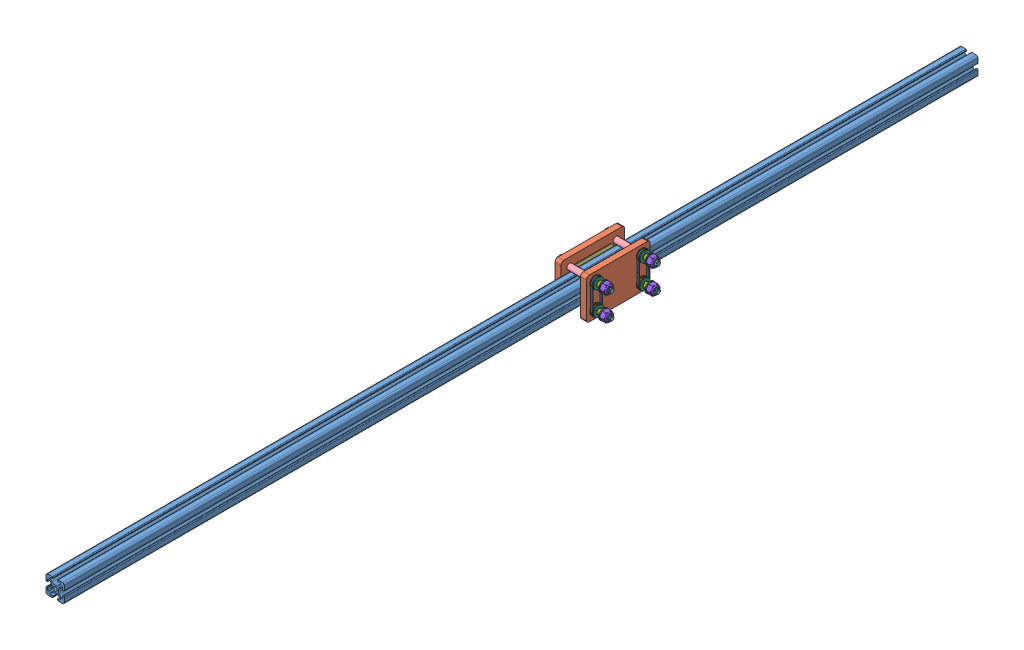
SolidWorks assembly Carriage, configuration Default. Lengths in mm.
Overall size (60.33 44.45 1000.12).
45 component instances, 10 part files, 37 mates.
Components (placement in the parent):
- 5537T237_T-Slotted Framing-1: 5537T237_T-Slotted Framing [5537T237] at origin size (19.99 19.99 1000.12)
- CarriagePlateHorizontal-1: CarriagePlateHorizontal [Default] at (17.1374 0 -99.2196) x (0 -1 0) z (-1 0 0) size (44.45 69.85 6.35)
- CarriagePlateHorizontal-2: CarriagePlateHorizontal [Default] at (-10.7874 0 -99.2196) x (0 -1 0) z (-1 0 0) size (44.45 69.85 6.35)
- Delrin Slide-1: Delrin Slide [Default] at (10.3937 0 -99.2196) x (-1 0 0) z (0 0 1) size (0.79 25.4 57.15)
- Delrin Slide-2: Delrin Slide [Default] at (-10.3937 0 -99.2196) x (-1 0 0) z (0 0 1) size (0.79 25.4 57.15)
- 8579K12 - Delrin Rod-1: 8579K12 - Delrin Rod [Default] at (0 13.175 -124.6196) x (0 -0.841097 0.540884) z (1 0 0) size (6.35 6.35 21.5)
- 91255A815_Button Head Hex Drive Screw-1: 91255A815_Button Head Hex Drive Screw [91255A815] at (-23.843 13.175 -124.6196) x (0 -0.96435 -0.26463) z (-1 0 0) size (9.17 9.17 60.33)
- 96765A125_Black-Oxide 18-8 Stainless Steel Washer-1: 96765A125_Black-Oxide 18-8 Stainless Steel Washer [96765A125] at (-21.2776 13.175 -124.6196) x (0 -0.999948 0.010183) z (0 0.010183 0.999948) size (11.11 0.97 11.11)
- 1986K71_302 Stainless Steel Corrosion-Resistant Compression Springs-1: 1986K71_302 Stainless Steel Corrosion-Resistant Compression Springs [Compressed] at (21.2776 13.175 -124.6196) x (0 -0.96435 -0.26463) z (-1 0 0) size (6.35 6.35 5.59)
- 96765A125_Black-Oxide 18-8 Stainless Steel Washer-2: 96765A125_Black-Oxide 18-8 Stainless Steel Washer [96765A125] at (20.3124 13.175 -124.6196) x (0 -0.999948 0.010183) z (0 0.010183 0.999948) size (11.11 0.97 11.11)
- 96765A125_Black-Oxide 18-8 Stainless Steel Washer-3: 96765A125_Black-Oxide 18-8 Stainless Steel Washer [96765A125] at (26.3576 13.175 -124.6196) x (0 -0.999948 0.010183) z (0 0.010183 0.999948) size (11.11 0.97 11.11)
- 94407A113_18-8 Stainless Steel Nylon-Insert Locknut-1: 94407A113_18-8 Stainless Steel Nylon-Insert Locknut [94407A113] at (27.3228 13.175 -124.6196) x (0 -0.999948 0.010183) z (0 0.010183 0.999948) size (9.53 6.11 11)
- 91255A815_Button Head Hex Drive Screw-2: 91255A815_Button Head Hex Drive Screw [91255A815] at (-23.843 -13.175 -73.8196) x (0 -0.96435 -0.26463) z (-1 0 0) size (9.17 9.17 60.33)
- 91255A815_Button Head Hex Drive Screw-3: 91255A815_Button Head Hex Drive Screw [91255A815] at (-23.843 -13.175 -124.6196) x (0 -0.96435 -0.26463) z (-1 0 0) size (9.17 9.17 60.33)
- 91255A815_Button Head Hex Drive Screw-5: 91255A815_Button Head Hex Drive Screw [91255A815] at (-23.843 13.175 -73.8196) x (0 -0.96435 -0.26463) z (-1 0 0) size (9.17 9.17 60.33)
- 96765A125_Black-Oxide 18-8 Stainless Steel Washer-4: 96765A125_Black-Oxide 18-8 Stainless Steel Washer [96765A125] at (-21.2776 -13.175 -73.8196) x (0 -0.999948 0.010183) z (0 0.010183 0.999948) size (11.11 0.97 11.11)
- 96765A125_Black-Oxide 18-8 Stainless Steel Washer-5: 96765A125_Black-Oxide 18-8 Stainless Steel Washer [96765A125] at (-21.2776 -13.175 -124.6196) x (0 -0.999948 0.010183) z (0 0.010183 0.999948) size (11.11 0.97 11.11)
- 96765A125_Black-Oxide 18-8 Stainless Steel Washer-7: 96765A125_Black-Oxide 18-8 Stainless Steel Washer [96765A125] at (-21.2776 13.175 -73.8196) x (0 -0.999948 0.010183) z (0 0.010183 0.999948) size (11.11 0.97 11.11)
- 8579K12 - Delrin Rod-2: 8579K12 - Delrin Rod [Default] at (0 -13.175 -73.8196) x (0 -0.841097 0.540884) z (1 0 0) size (6.35 6.35 21.5)
- 8579K12 - Delrin Rod-3: 8579K12 - Delrin Rod [Default] at (0 -13.175 -124.6196) x (0 -0.841097 0.540884) z (1 0 0) size (6.35 6.35 21.5)
- 8579K12 - Delrin Rod-5: 8579K12 - Delrin Rod [Default] at (0 13.175 -73.8196) x (0 -0.841097 0.540884) z (1 0 0) size (6.35 6.35 21.5)
- 96765A125_Black-Oxide 18-8 Stainless Steel Washer-8: 96765A125_Black-Oxide 18-8 Stainless Steel Washer [96765A125] at (20.3124 -13.175 -73.8196) x (0 -0.999948 0.010183) z (0 0.010183 0.999948) size (11.11 0.97 11.11)
- 96765A125_Black-Oxide 18-8 Stainless Steel Washer-9: 96765A125_Black-Oxide 18-8 Stainless Steel Washer [96765A125] at (20.3124 -13.175 -124.6196) x (0 -0.999948 0.010183) z (0 0.010183 0.999948) size (11.11 0.97 11.11)
- 96765A125_Black-Oxide 18-8 Stainless Steel Washer-11: 96765A125_Black-Oxide 18-8 Stainless Steel Washer [96765A125] at (20.3124 13.175 -73.8196) x (0 -0.999948 0.010183) z (0 0.010183 0.999948) size (11.11 0.97 11.11)
- 1986K71_302 Stainless Steel Corrosion-Resistant Compression Springs-2: 1986K71_302 Stainless Steel Corrosion-Resistant Compression Springs [Compressed] at (21.2776 -13.175 -73.8196) x (0 -0.96435 -0.26463) z (-1 0 0) size (6.35 6.35 5.59)
- 1986K71_302 Stainless Steel Corrosion-Resistant Compression Springs-3: 1986K71_302 Stainless Steel Corrosion-Resistant Compression Springs [Compressed] at (21.2776 -13.175 -124.6196) x (0 -0.96435 -0.26463) z (-1 0 0) size (6.35 6.35 5.59)
- 1986K71_302 Stainless Steel Corrosion-Resistant Compression Springs-5: 1986K71_302 Stainless Steel Corrosion-Resistant Compression Springs [Compressed] at (21.2776 13.175 -73.8196) x (0 -0.96435 -0.26463) z (-1 0 0) size (6.35 6.35 5.59)
- 94407A113_18-8 Stainless Steel Nylon-Insert Locknut-2: 94407A113_18-8 Stainless Steel Nylon-Insert Locknut [94407A113] at (27.3228 -13.175 -73.8196) x (0 -0.999948 0.010183) z (0 0.010183 0.999948) size (9.53 6.11 11)
- 94407A113_18-8 Stainless Steel Nylon-Insert Locknut-3: 94407A113_18-8 Stainless Steel Nylon-Insert Locknut [94407A113] at (27.3228 -13.175 -124.6196) x (0 -0.999948 0.010183) z (0 0.010183 0.999948) size (9.53 6.11 11)
- 94407A113_18-8 Stainless Steel Nylon-Insert Locknut-5: 94407A113_18-8 Stainless Steel Nylon-Insert Locknut [94407A113] at (27.3228 13.175 -73.8196) x (0 -0.999948 0.010183) z (0 0.010183 0.999948) size (9.53 6.11 11)
- 96765A125_Black-Oxide 18-8 Stainless Steel Washer-12: 96765A125_Black-Oxide 18-8 Stainless Steel Washer [96765A125] at (26.3576 -13.175 -73.8196) x (0 -0.999948 0.010183) z (0 0.010183 0.999948) size (11.11 0.97 11.11)
- 96765A125_Black-Oxide 18-8 Stainless Steel Washer-13: 96765A125_Black-Oxide 18-8 Stainless Steel Washer [96765A125] at (26.3576 -13.175 -124.6196) x (0 -0.999948 0.010183) z (0 0.010183 0.999948) size (11.11 0.97 11.11)
- 96765A125_Black-Oxide 18-8 Stainless Steel Washer-15: 96765A125_Black-Oxide 18-8 Stainless Steel Washer [96765A125] at (26.3576 13.175 -73.8196) x (0 -0.999948 0.010183) z (0 0.010183 0.999948) size (11.11 0.97 11.11)
- O-Ring Tensioner-1: O-Ring Tensioner [Default] at (-18.7249 13.175 -124.6196) size (3.17 11.5 11.5)
- O-Ring Tensioner-2: O-Ring Tensioner [Default] at (-18.7249 -13.175 -73.8196) size (3.17 11.5 11.5)
- O-Ring Tensioner-3: O-Ring Tensioner [Default] at (-18.7249 -13.175 -124.6196) size (3.17 11.5 11.5)
- O-Ring Tensioner-4: O-Ring Tensioner [Default] at (-18.7249 13.175 -73.8196) size (3.17 11.5 11.5)
- O-Ring Tensioner-5: O-Ring Tensioner [Default] at (18.7249 13.175 -124.6196) size (3.17 11.5 11.5)
- O-Ring Tensioner-6: O-Ring Tensioner [Default] at (18.7249 -13.175 -73.8196) size (3.17 11.5 11.5)
- O-Ring Tensioner-7: O-Ring Tensioner [Default] at (18.7249 -13.175 -124.6196) size (3.17 11.5 11.5)
- O-Ring Tensioner-8: O-Ring Tensioner [Default] at (18.7249 13.175 -73.8196) size (3.17 11.5 11.5)
- O-ring-1: O-ring [Default] at (-18.7249 0 -124.6196) x (0 0 1) z (-1 0 0) size (12.13 38.48 1.78)
- O-ring-2: O-ring [Default] at (-18.7249 0 -73.8196) x (0 0 1) z (-1 0 0) size (12.13 38.48 1.78)
- O-ring-3: O-ring [Default] at (18.7249 0 -124.6196) x (0 0 1) z (-1 0 0) size (12.13 38.48 1.78)
- O-ring-4: O-ring [Default] at (18.7249 0 -73.8196) x (0 0 1) z (-1 0 0) size (12.13 38.48 1.78)
Mates (geometry in assembly coordinates):
- Coincident1: coordinate: unknown of 5537T237_T-Slotted Framing-1
- Concentric1: concentric aligned: cylinder of CarriagePlateHorizontal-1 through (10.7874 13.175 -73.8196) axis (1 0 0) radius 2.7305; cylinder of CarriagePlateHorizontal-2 through (-17.1374 13.175 -73.8196) axis (1 0 0) radius 2.7305
- Coincident5: coincident aligned: plane of CarriagePlateHorizontal-1 through (17.1374 0 -99.2196) normal (0 0 1); plane of CarriagePlateHorizontal-2 through (-10.7874 0 -99.2196) normal (0 0 1)
- Coincident11: coincident anti-aligned: plane of CarriagePlateHorizontal-1 through (10.7874 0 -99.2196) normal (-1 0 0); plane of Delrin Slide-1 through (10.7874 -12.7 -70.6446) normal (1 0 0)
- Coincident12: coincident aligned: plane of CarriagePlateHorizontal-1 through (17.1374 0 -99.2196) normal (0 0 1); plane of Delrin Slide-1 through (10.3937 0 -99.2196) normal (0 0 1)
- Coincident13: coincident aligned: plane of CarriagePlateHorizontal-1 through (17.1374 0 -99.2196) normal (0 -1 0); plane of Delrin Slide-1 through (10.3937 0 -99.2196) normal (0 -1 0)
- Coincident14: coincident anti-aligned: plane of CarriagePlateHorizontal-2 through (-10.7874 0 -99.2196) normal (1 0 0); plane of Delrin Slide-2 through (-10.7874 -12.7 -70.6446) normal (-1 0 0)
- Coincident15: coincident aligned: plane of CarriagePlateHorizontal-2 through (-10.7874 0 -99.2196) normal (0 0 1); plane of Delrin Slide-2 through (-10.3937 0 -99.2196) normal (0 0 1)
- Coincident16: coincident aligned: plane of CarriagePlateHorizontal-2 through (-10.7874 0 -99.2196) normal (0 -1 0); plane of Delrin Slide-2 through (-10.3937 0 -99.2196) normal (0 -1 0)
- Distance2: distance = 20 mm anti-aligned: plane of Delrin Slide-2 through (-10 -12.7 -70.6446) normal (1 0 0); plane of Delrin Slide-1 through (10 -12.7 -70.6446) normal (-1 0 0)
- Concentric13: concentric aligned: cylinder of 8579K12 - Delrin Rod-1 through (10.75 13.175 -124.6196) axis (-1 0 0) radius 2.413; cylinder of 91255A815_Button Head Hex Drive Screw-1 through (-21.2776 13.175 -124.6196) axis (-1 0 0) radius 2.413
- Coincident38: coincident anti-aligned: plane of 91255A815_Button Head Hex Drive Screw-1 through (-21.2776 14.3882 -129.0409) normal (1 0 0); plane of 96765A125_Black-Oxide 18-8 Stainless Steel Washer-1 through (-21.2776 13.175 -124.6196) normal (-1 0 0)
- Concentric14: concentric anti-aligned: cylinder of 91255A815_Button Head Hex Drive Screw-1 through (-21.2776 13.175 -124.6196) axis (-1 0 0) radius 2.413; cylinder of 96765A125_Black-Oxide 18-8 Stainless Steel Washer-1 through (-21.2776 13.175 -124.6196) axis (1 0 0) radius 2.5781
- Coincident39: coincident anti-aligned: plane of O-Ring Tensioner-1 through (-20.3124 13.175 -124.6196) normal (-1 0 0); plane of 96765A125_Black-Oxide 18-8 Stainless Steel Washer-1 through (-20.3124 13.175 -124.6196) normal (1 0 0)
- Coincident40: coincident aligned: plane of 91255A815_Button Head Hex Drive Screw-1 through (-23.843 13.175 -124.6196) normal (0 -0.26463 0.96435); plane of 1986K71_302 Stainless Steel Corrosion-Resistant Compression Springs-1 through (21.2776 13.175 -124.6196) normal (0 -0.26463 0.96435)
- Coincident41: coincident aligned: plane of 91255A815_Button Head Hex Drive Screw-1 through (-23.843 13.175 -124.6196) normal (0 -0.96435 -0.26463); plane of 1986K71_302 Stainless Steel Corrosion-Resistant Compression Springs-1 through (21.2776 13.175 -124.6196) normal (0 -0.96435 -0.26463)
- Concentric15: concentric anti-aligned: cylinder of 91255A815_Button Head Hex Drive Screw-1 through (-21.2776 13.175 -124.6196) axis (-1 0 0) radius 2.413; cylinder of 96765A125_Black-Oxide 18-8 Stainless Steel Washer-2 through (20.3124 13.175 -124.6196) axis (1 0 0) radius 2.5781
- Coincident44: coincident anti-aligned: plane of O-Ring Tensioner-5 through (20.3124 18.925 -124.6196) normal (1 0 0); plane of 96765A125_Black-Oxide 18-8 Stainless Steel Washer-2 through (20.3124 13.175 -124.6196) normal (-1 0 0)
- Coincident45: coincident anti-aligned: plane of 1986K71_302 Stainless Steel Corrosion-Resistant Compression Springs-1 through (21.2776 13.175 -124.6196) normal (-1 0 0); plane of 96765A125_Black-Oxide 18-8 Stainless Steel Washer-2 through (21.2776 13.175 -124.6196) normal (1 0 0)
- Concentric16: concentric anti-aligned: cylinder of 91255A815_Button Head Hex Drive Screw-1 through (-21.2776 13.175 -124.6196) axis (-1 0 0) radius 2.413; cylinder of 96765A125_Black-Oxide 18-8 Stainless Steel Washer-3 through (26.3576 13.175 -124.6196) axis (1 0 0) radius 2.5781
- Distance3: distance = 5.08 mm anti-aligned: plane of 96765A125_Black-Oxide 18-8 Stainless Steel Washer-2 through (21.2776 13.175 -124.6196) normal (1 0 0); plane of 96765A125_Black-Oxide 18-8 Stainless Steel Washer-3 through (26.3576 13.175 -124.6196) normal (-1 0 0)
- Concentric17: concentric aligned: cylinder of 91255A815_Button Head Hex Drive Screw-1 through (-21.2776 13.175 -124.6196) axis (-1 0 0) radius 2.413; cylinder of 94407A113_18-8 Stainless Steel Nylon-Insert Locknut-1 through (32.3599 13.175 -124.6196) axis (-1 0 0) radius 2.0454
- Coincident47: coincident anti-aligned: plane of 96765A125_Black-Oxide 18-8 Stainless Steel Washer-3 through (27.3228 13.175 -124.6196) normal (1 0 0); plane of 94407A113_18-8 Stainless Steel Nylon-Insert Locknut-1 through (27.3228 17.8533 -132.9166) normal (-1 0 0)
- Concentric18: concentric anti-aligned: cylinder of CarriagePlateHorizontal-2 through (-17.1374 13.175 -124.6196) axis (1 0 0) radius 2.7305; cylinder of 91255A815_Button Head Hex Drive Screw-1 through (-21.2776 13.175 -124.6196) axis (-1 0 0) radius 2.413
- Coincident48: coincident anti-aligned: plane of 5537T237_T-Slotted Framing-1 through (0 0 0) normal (0 1 0); plane of CarriagePlateHorizontal-2 through (-10.7874 0 -99.2196) normal (0 -1 0)
- Coincident49: coincident aligned: plane of 8579K12 - Delrin Rod-1 through (0 13.175 -124.6196) normal (1 0 0)
- Symmetric1: symmetric aligned: plane of CarriagePlateHorizontal-1 through (10.7874 0 -99.2196) normal (-1 0 0); plane of CarriagePlateHorizontal-2 through (-10.7874 0 -99.2196) normal (1 0 0)
- Coincident50: coincident anti-aligned: plane of CarriagePlateHorizontal-2 through (-17.1374 0 -99.2196) normal (-1 0 0); plane of O-Ring Tensioner-1 through (-17.1374 18.925 -124.6196) normal (1 0 0)
- Concentric19: concentric anti-aligned: cylinder of 91255A815_Button Head Hex Drive Screw-1 through (-21.2776 13.175 -124.6196) axis (-1 0 0) radius 2.413; cylinder of O-Ring Tensioner-1 through (-20.3124 13.175 -124.6196) axis (1 0 0) radius 2.54
- Coincident51: coincident anti-aligned: plane of CarriagePlateHorizontal-1 through (17.1374 0 -99.2196) normal (1 0 0); plane of O-Ring Tensioner-5 through (17.1374 13.175 -124.6196) normal (-1 0 0)
- Concentric20: concentric anti-aligned: cylinder of 8579K12 - Delrin Rod-1 through (10.75 13.175 -124.6196) axis (-1 0 0) radius 2.413; cylinder of O-Ring Tensioner-5 through (17.1374 13.175 -124.6196) axis (1 0 0) radius 2.54
- Concentric21: concentric: cylinder of 91255A815_Button Head Hex Drive Screw-1 through (-23.843 13.175 -124.6196) axis (-1 0 0) radius 4.5847
- Parallel1: parallel anti-aligned: plane of CarriagePlateHorizontal-2 through (-17.1374 -22.225 -134.1446) normal (0 -1 0); plane of O-ring-1 through (-18.7249 0 -124.6196) normal (0 1 0)
- Coincident54: coincident aligned: plane of O-ring-1 through (-18.7249 0 -124.6196) normal (-1 0 0); plane of O-ring-2 through (-18.7249 0 -73.8196) normal (-1 0 0)
- Coincident55: coincident aligned: plane of O-ring-1 through (-18.7249 0 -124.6196) normal (0 1 0); plane of O-ring-2 through (-18.7249 0 -73.8196) normal (0 1 0)
- Distance4: distance = 50.8 mm aligned: plane of O-ring-2 through (-18.7249 0 -73.8196) normal (0 0 1); plane of O-ring-1 through (-18.7249 0 -124.6196) normal (0 0 1)
- Coincident56: coincident anti-aligned: plane of O-Ring Tensioner-1 through (-18.7249 13.175 -124.6196) normal (1 0 0); plane of O-ring-1 through (-18.7249 0 -124.6196) normal (-1 0 0)
